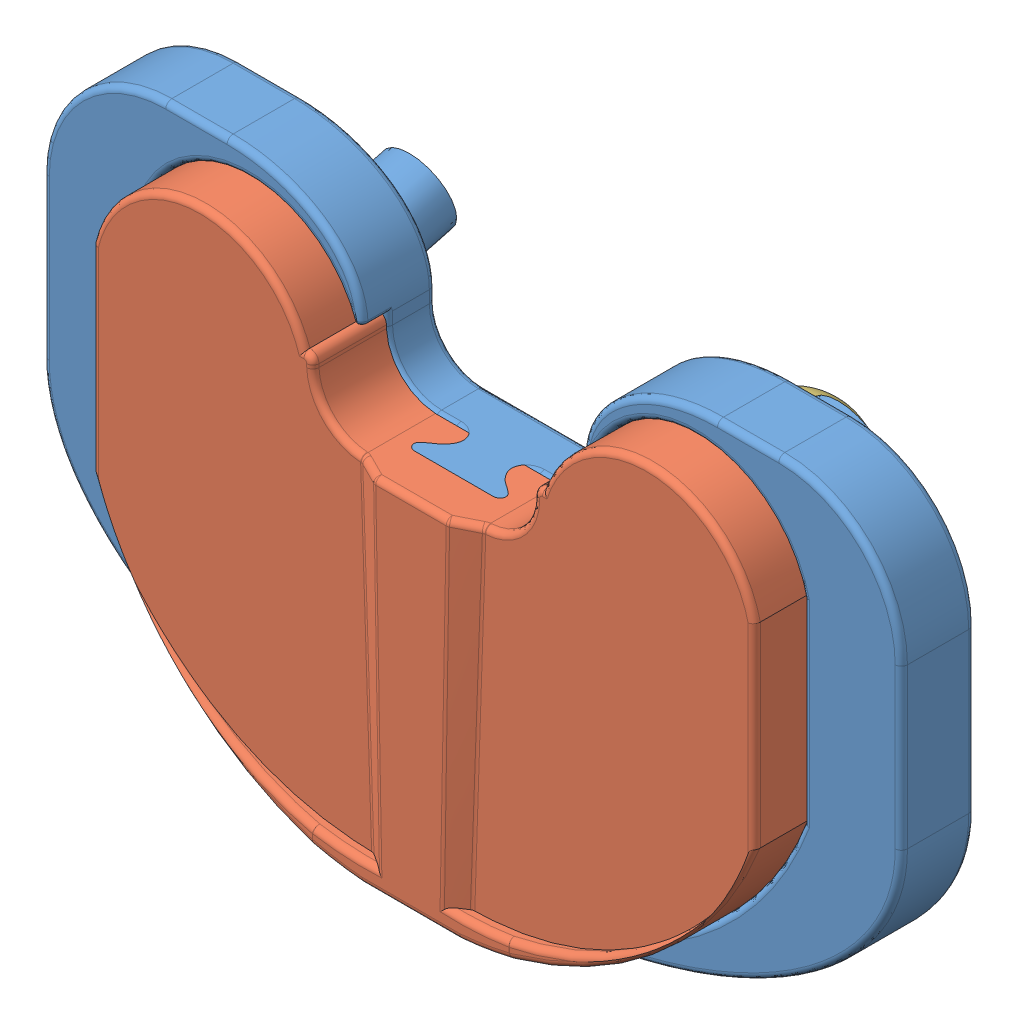
SolidWorks assembly Gruppo3_pezzo7_assieme, configuration Default. Lengths in mm.
Overall size (76.02 46.68 38.31).
5 component instances, 4 part files, 7 mates.
Components (placement in the parent):
- Gruppo3_pezzo7_ParteMetallica-1: Gruppo3_pezzo7_ParteMetallica [Default] at (-6.8812 -15.5362 76.0187) size (76.02 46.68 26.69)
- Gruppo3_pezzo7_ParteBianca-1: Gruppo3_pezzo7_ParteBianca [Default] at (-6.8812 -15.5362 80.0187) size (54 40.26 8.26)
- Gruppo3_pezzo7_Vite-2: Gruppo3_pezzo7_Vite [Default] at (-6.8812 -0.0509 58.7298) x (-0.977968 0.201643 0.05403) z (-0.208757 -0.944644 -0.253117) size (10 16 10)
- Gruppo3_pezzo7_Tappino-1: Gruppo3_pezzo7_Tappino [Default] at (10.6188 18.5231 68.8831) x (1 0 0) z (0 -0.258819 0.965926) size (3.5 3.5 3)
- Gruppo3_pezzo7_Tappino-3: Gruppo3_pezzo7_Tappino [Default] at (-24.3812 18.5231 68.8831) x (0.419259 0.876932 0.234973) z (0 -0.258819 0.965926) size (3.5 3.5 3)
Mates (geometry in assembly coordinates):
- Coincidente1: coincident anti-aligned: plane of Parte_metallica_nomi-1 through (-2.0767 18.6593 80.0187) normal (0 0 1); plane of Parte bianca-1 through (-5.1194 12.1209 80.0187) normal (0 0 -1)
- Coincidente2: coincident aligned: line of Parte_metallica_nomi-1 through (-33.8812 2.5275 80.0187) axis (0 1 0); line of Parte bianca-1 through (-33.8812 2.5275 80.0187) axis (0 1 0)
- Coincidente3: coincident aligned: circle of Parte_metallica_nomi-1; circle of ParteBianca-1
- Concentrico3: concentric anti-aligned: circle of Parte metallica-1; circle of Vite-2
- Coincidente7: coincident anti-aligned: circle of Parte metallica-1; circle of Vite-2
- Coincidente8: coincident anti-aligned: circle of Parte metallica-1; circle of Tappino-1
- Coincidente9: coincident aligned: circle of Parte metallica-1; circle of Tappino-3
